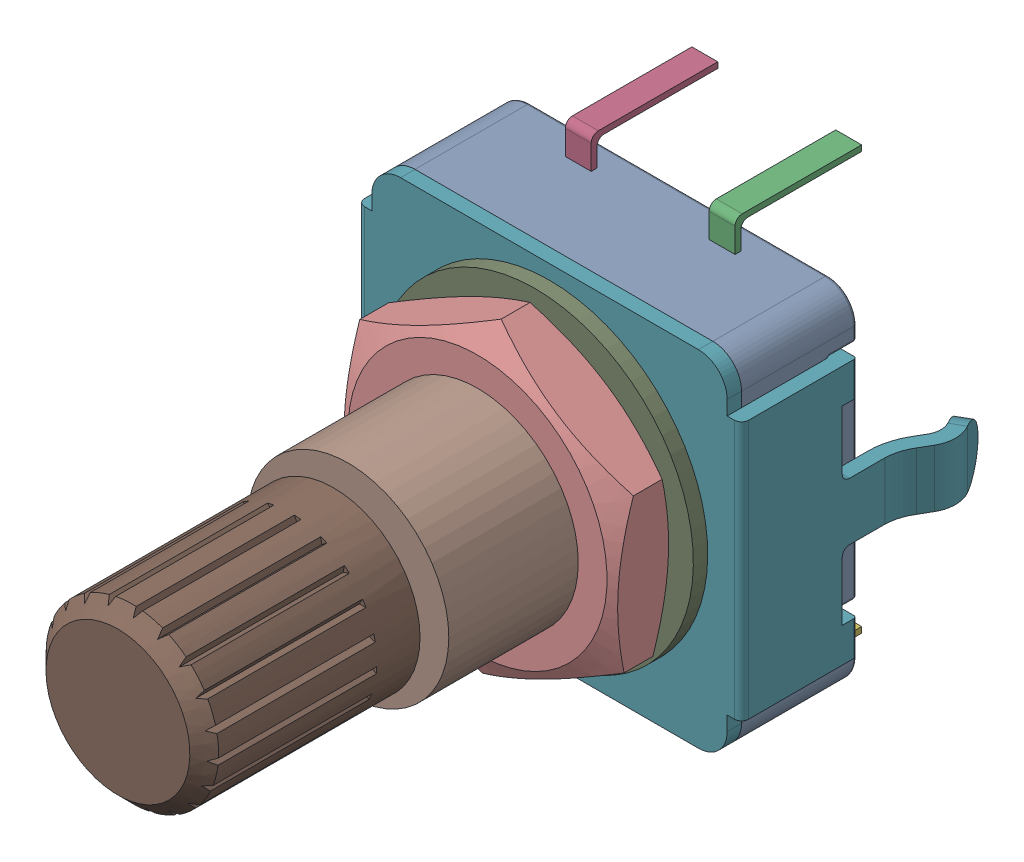
SolidWorks assembly EN1, configuration Default. Lengths in mm.
Overall size (14.62 14.7 23.24).
12 component instances, 7 part files, 0 mates.
Components (placement in the parent):
- PEC11_4220_S0024-1: PEC11_4220_S0024 [Default] at (90.0001 27.7501 0) x (1 0 0) z (0 0 1) size (14.62 14.7 23.24)
  - 12mm_Incremental_Encoder_Base_1-1: 12mm_Incremental_Encoder_Base_1 [Default] at origin size (12.36 12 4)
  - 12mm_Incremental_Encoder_Pin_1-1: 12mm_Incremental_Encoder_Pin_1 [Default] at (0 -6.6 0.8) x (0 -1 0) z (-1 0 0) size (3 4.4 0.9)
  - 12mm_Incremental_Encoder_Pin_1-2: 12mm_Incremental_Encoder_Pin_1 [Default] at (2.5 6.1 0.8) x (0 1 0) z (1 0 0) size (3 4.4 0.9)
  - 12mm_Incremental_Encoder_Pin_1-3: 12mm_Incremental_Encoder_Pin_1 [Default] at (-2.5 6.1 0.8) x (0 1 0) z (1 0 0) size (3 4.4 0.9)
  - 12mm_Incremental_Encoder_Pin_1-4: 12mm_Incremental_Encoder_Pin_1 [Default] at (-2.5 -6.6 0.8) x (0 -1 0) z (-1 0 0) size (3 4.4 0.9)
  - 12mm_Incremental_Encoder_Pin_1-5: 12mm_Incremental_Encoder_Pin_1 [Default] at (2.5 -6.6 0.8) x (0 -1 0) z (-1 0 0) size (3 4.4 0.9)
  - 12mm_Incremental_Encoder_Anti-Rotation_Plate_1-1: 12mm_Incremental_Encoder_Anti-Rotation_Plate_1 [Default] at (0 0 4) size (14.62 12 8.24)
  - 12mm_Incremental_Encoder_Threaded_Tube_1-1: 12mm_Incremental_Encoder_Threaded_Tube_1 [Default] at (-5.8861 -2.5756 11.5) x (-0.916131 -0.400879 0) z (0 0 -1) size (7 7 7)
  - 12mm_Incremental_Encoder_Washer_1-1: 12mm_Incremental_Encoder_Washer_1 [Default] at (6.424 -0.1143 4.5) x (0.999842 -0.017794 0) z (0 0 1) size (11 11 0.5)
  - M7x0.75_Hex_Nut_1-1: M7x0.75_Hex_Nut_1 [Default] at (0 0 5) x (0.835271 -0.549838 0) z (0 0 1) size (11 9.53 2)
  - 12mm_Incremental_Encoder_Shaft-1: 12mm_Incremental_Encoder_Shaft [Default] at (0 0 11.5) x (0.652489 0.757799 0) z (0 0 1) size (6 6 13)
